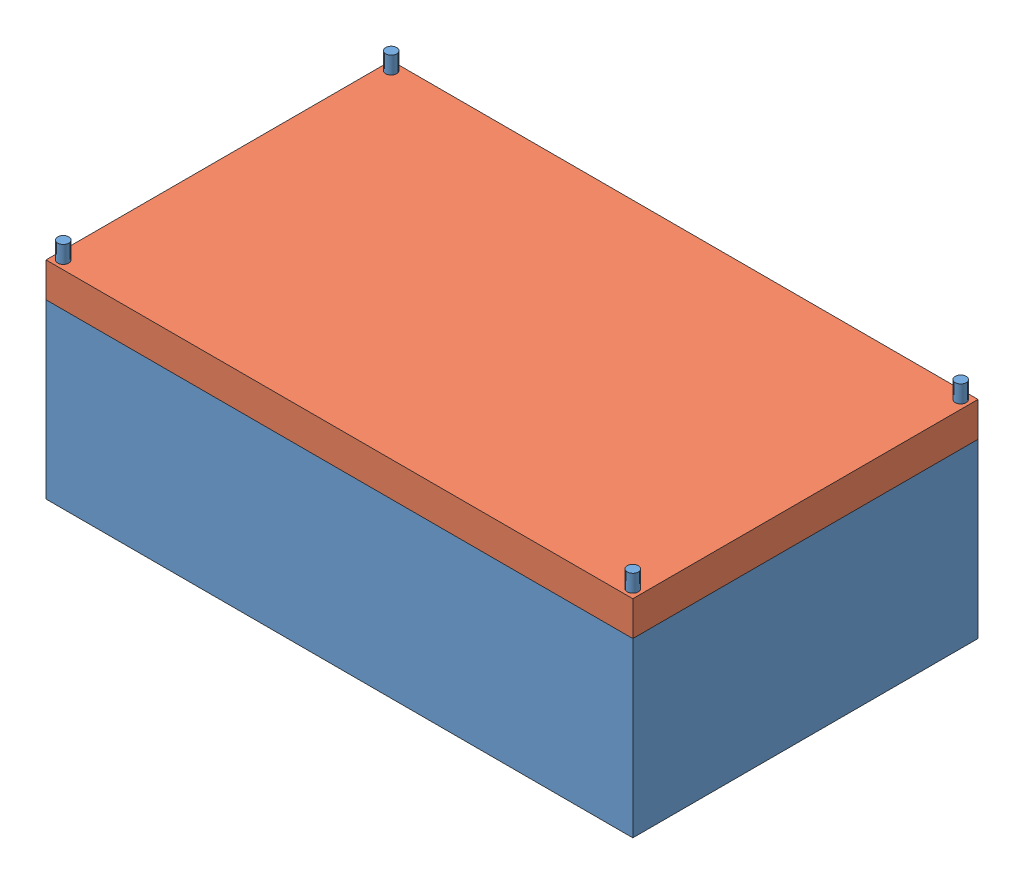
SolidWorks assembly Box Casing for Headset, configuration Default. Lengths in mm.
Overall size (170 65 100).
2 component instances, 2 part files, 3 mates.
Components (placement in the parent):
- Headset Top-1: Headset Top [Default] at (77.8589 59.6498 142.6362) size (170 65 100)
- Headset cover-1: Headset cover [Default] at (77.8589 119.6498 142.6362) x (-1 0 0) z (0 0 1) size (170 20 100)
Mates (geometry in assembly coordinates):
- Concentric1: concentric aligned: cylinder of Headset Top-1 through (160.3589 124.6498 190.1362) axis (0 -1 0) radius 1.6; circle of Headset cover-1
- Concentric2: concentric aligned: cylinder of Headset Top-1 through (-4.6411 124.6498 95.1362) axis (0 -1 0) radius 1.6; cylinder of Headset cover-1 through (-4.6411 119.6498 95.1362) axis (0 -1 0) radius 1.5
- Coincident1: coincident anti-aligned: plane of Headset Top-1 through (77.8589 109.6498 142.6362) normal (0 1 0); plane of Headset cover-1 through (77.8589 109.6498 142.6362) normal (0 -1 0)
